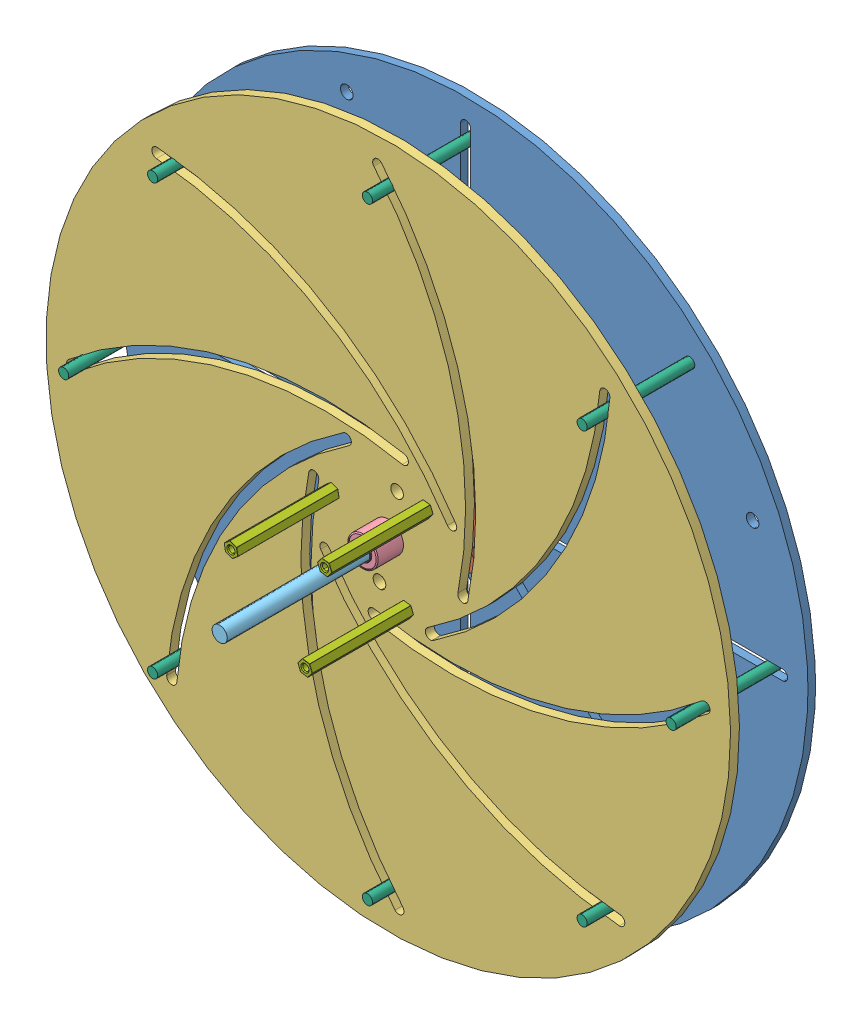
SolidWorks assembly face-clutch-sub, configuration Default. Lengths in mm.
Overall size (318.26 318.26 108.25).
16 component instances, 7 part files, 43 mates.
Components (placement in the parent):
- facePlate-2.0-1: facePlate-2.0 [Default] at origin size (270 270 3)
- flange-coupling-1: flange-coupling [Default] at (0 0 7) x (-1 0 0) z (0 0 -1) size (47 47 20)
- clutchPlate-2.0-1: clutchPlate-2.0 [Default] at (0 0 31.75) x (-0.19867 -0.980066 0) z (0 0 1) size (270 270 3.5)
- LMF6-1: LMF6 [Default] at (0 0 30) x (0.19867 0.980066 0) z (0 0 -1) size (45 45 19)
- shaft-1: shaft [Default] at (0 0 50) x (0.678945 0.734189 0) z (0 0 1) size (6 6 100)
- spoke-1: spoke [Default] at (-84.7044 -84.7044 16.75) x (0.340685 0.940177 0) z (0 0 1) size (4 4 50)
- spoke-2: spoke [Default] at (-119.7901 0 16.75) x (0.626518 0.779407 0) z (0 0 1) size (4 4 50)
- spoke-3: spoke [Default] at (-84.7044 84.7044 16.75) x (-0.525078 0.851054 0) z (0 0 1) size (4 4 50)
- spoke-4: spoke [Default] at (0 119.7901 16.75) x (0.971172 -0.238381 0) z (0 0 1) size (4 4 50)
- spoke-5: spoke [Default] at (84.7044 84.7044 16.75) x (-0.23415 0.9722 0) z (0 0 1) size (4 4 50)
- spoke-6: spoke [Default] at (119.7901 0 16.75) x (-0.955181 0.296022 0) z (0 0 1) size (4 4 50)
- spoke-7: spoke [Default] at (84.7044 -84.7044 16.75) size (4 4 50)
- spoke-8: spoke [Default] at (0 -119.7901 16.75) size (4 4 50)
- TFF-M3x40_DR113.step-1: TFF-M3x40_DR113.step [Default] at (-22.0515 4.4701 73.5) x (0 0 -1) z (-0.344816 -0.93867 0) size (40 5.74 5)
- TFF-M3x40_DR113.step-2: TFF-M3x40_DR113.step [Default] at (14.8969 16.8621 73.5) x (0 0 -1) z (0.79908 -0.601224 0) size (40 5.74 5)
- TFF-M3x40_DR113.step-3: TFF-M3x40_DR113.step [Default] at (7.1546 -21.3322 73.5) x (0 0 -1) z (-0.929232 -0.369496 0) size (40 5.74 5)
Mates (geometry in assembly coordinates):
- Coincident1: coordinate: point of facePlate-2.0-1
- Parallel1: parallel aligned: plane of facePlate-2.0-1 through (0 0 0) normal (0 1 0)
- Concentric1: concentric anti-aligned: cylinder of flange-coupling-1 through (0 0 3) axis (0 0 1) radius 3; cylinder of facePlate-2.0-1 through (0 0 3) axis (0 0 -1) radius 135
- Concentric2: concentric aligned: cylinder of flange-coupling-1 through (8.75 15.1554 23) axis (0 0 -1) radius 2.5; cylinder of facePlate-2.0-1 through (8.75 15.1554 3) axis (0 0 -1) radius 2.5
- Concentric4: concentric aligned: circle of facePlate-2.0-1; circle of clutchPlate-2.0-1
- Distance1: distance = 27 mm anti-aligned: plane of facePlate-2.0-1 through (0 0 3) normal (0 0 1); plane of clutchPlate-2.0-1 through (0 0 30) normal (0 0 -1)
- Coincident4: coincident anti-aligned: plane of facePlate-2.0-1 through (0 0 3) normal (0 0 1); plane of flange-coupling-1 through (0 0 3) normal (0 0 -1)
- Coincident5: coincident anti-aligned: plane of clutchPlate-2.0-1 through (0 0 30) normal (0 0 -1); plane of LMF6-1 through (0 0 30) normal (0 0 1)
- Concentric5: concentric aligned: cylinder of clutchPlate-2.0-1 through (0 0 30) axis (0 0 1) radius 5; cylinder of LMF6-1 through (0 0 25) axis (0 0 1) radius 22.5
- Concentric6: concentric anti-aligned: cylinder of LMF6-1 through (3.4767 17.1512 44) axis (0 0 -1) radius 1.75; cylinder of clutchPlate-2.0-1 through (3.4767 17.1512 30) axis (0 0 1) radius 2.5
- Concentric7: concentric aligned: cylinder of flange-coupling-1 through (0 0 3) axis (0 0 1) radius 3; cylinder of shaft-1 through (0 0 0) axis (0 0 1) radius 3
- Coincident6: coincident aligned: plane of facePlate-2.0-1 through (0 0 0) normal (0 0 -1); plane of shaft-1 through (0 0 0) normal (0 0 -1)
- Slot1: slot aligned: cylinder of spoke-1 through (-84.7044 -84.7044 -8.25) axis (0 0 1) radius 2; cylinder of clutchPlate-2.0-1 through (69.0664 -104.1866 30) axis (0 0 1) radius 153; cylinder of clutchPlate-2.0-1 through (-85.3956 -91.283 30) axis (0 0 1) radius 2
- Slot2: slot anti-aligned: plane of facePlate-2.0-1 through (-22.6274 19.799 3) normal (0.707107 0.707107 0); cylinder of spoke-3 through (-84.7044 84.7044 -8.25) axis (0 0 1) radius 2; cylinder of facePlate-2.0-1 through (-88.3883 88.3883 3) axis (0 0 -1) radius 2
- Width1: width anti-aligned: plane of spoke-1 through (-84.7044 -84.7044 -8.25) normal (0 0 -1); plane of spoke-1 through (-84.7044 -84.7044 41.75) normal (0 0 1); plane of clutchPlate-2.0-1 through (0 0 33.5) normal (0 0 1); plane of facePlate-2.0-1 through (0 0 0) normal (0 0 -1)
- Slot3: slot anti-aligned: cylinder of spoke-1 through (-84.7044 -84.7044 -8.25) axis (0 0 1) radius 2; plane of facePlate-2.0-1 through (-19.799 -22.6274 3) normal (-0.707107 0.707107 0); cylinder of facePlate-2.0-1 through (-88.3883 -88.3883 3) axis (0 0 -1) radius 2
- Slot4: slot anti-aligned: cylinder of spoke-2 through (-119.7901 0 -8.25) axis (0 0 1) radius 2; plane of facePlate-2.0-1 through (-30 -2 3) normal (0 1 0); cylinder of facePlate-2.0-1 through (-125 0 3) axis (0 0 -1) radius 2
- Slot5: slot aligned: cylinder of spoke-2 through (-119.7901 0 -8.25) axis (0 0 1) radius 2; cylinder of clutchPlate-2.0-1 through (-24.8337 -122.5083 30) axis (0 0 1) radius 153; cylinder of clutchPlate-2.0-1 through (-124.9307 -4.163 30) axis (0 0 1) radius 2
- Width2: width anti-aligned: plane of spoke-2 through (-119.7901 0 41.75) normal (0 0 1); plane of spoke-2 through (-119.7901 0 -8.25) normal (0 0 -1); plane of facePlate-2.0-1 through (0 0 0) normal (0 0 -1); plane of clutchPlate-2.0-1 through (0 0 33.5) normal (0 0 1)
- Slot7: slot aligned: cylinder of spoke-3 through (-84.7044 84.7044 -8.25) axis (0 0 1) radius 2; cylinder of clutchPlate-2.0-1 through (-104.1866 -69.0664 30) axis (0 0 1) radius 153; cylinder of clutchPlate-2.0-1 through (-91.283 85.3956 30) axis (0 0 1) radius 2
- Slot8: slot anti-aligned: cylinder of spoke-3 through (-84.7044 84.7044 -8.25) axis (0 0 1) radius 2; cylinder of facePlate-2.0-1 through (-21.2132 21.2132 3) axis (0 0 -1) radius 2; cylinder of facePlate-2.0-1 through (-88.3883 88.3883 3) axis (0 0 -1) radius 2
- Slot9: slot aligned: cylinder of spoke-4 through (0 119.7901 -8.25) axis (0 0 1) radius 2; cylinder of clutchPlate-2.0-1 through (-122.5083 24.8337 30) axis (0 0 1) radius 157; cylinder of clutchPlate-2.0-1 through (-4.163 124.9307 30) axis (0 0 1) radius 2
- Slot10: slot anti-aligned: cylinder of spoke-4 through (0 119.7901 -8.25) axis (0 0 1) radius 2; plane of facePlate-2.0-1 through (2 30 3) normal (-1 0 0); cylinder of facePlate-2.0-1 through (0 30 3) axis (0 0 -1) radius 2
- Width3: width anti-aligned: plane of spoke-4 through (0 119.7901 41.75) normal (0 0 1); plane of spoke-4 through (0 119.7901 -8.25) normal (0 0 -1); plane of facePlate-2.0-1 through (0 0 0) normal (0 0 -1); plane of clutchPlate-2.0-1 through (0 0 33.5) normal (0 0 1)
- Slot11: slot aligned: cylinder of spoke-5 through (84.7044 84.7044 -8.25) axis (0 0 1) radius 2; cylinder of clutchPlate-2.0-1 through (-69.0664 104.1866 30) axis (0 0 1) radius 153; cylinder of clutchPlate-2.0-1 through (85.3956 91.283 30) axis (0 0 1) radius 2
- Slot12: slot anti-aligned: cylinder of spoke-5 through (84.7044 84.7044 -8.25) axis (0 0 1) radius 2; plane of facePlate-2.0-1 through (19.799 22.6274 3) normal (0.707107 -0.707107 0); cylinder of facePlate-2.0-1 through (88.3883 88.3883 3) axis (0 0 -1) radius 2
- Width4: width anti-aligned: plane of spoke-5 through (84.7044 84.7044 -8.25) normal (0 0 -1); plane of spoke-5 through (84.7044 84.7044 41.75) normal (0 0 1); plane of clutchPlate-2.0-1 through (0 0 33.5) normal (0 0 1); plane of facePlate-2.0-1 through (0 0 0) normal (0 0 -1)
- Slot13: slot anti-aligned: cylinder of spoke-6 through (119.7901 0 -8.25) axis (0 0 1) radius 2; plane of facePlate-2.0-1 through (30 -2 3) normal (0 1 0); cylinder of facePlate-2.0-1 through (30 0 3) axis (0 0 -1) radius 2
- Slot14: slot aligned: cylinder of spoke-6 through (119.7901 0 -8.25) axis (0 0 1) radius 2; cylinder of clutchPlate-2.0-1 through (24.8337 122.5083 30) axis (0 0 1) radius 153; cylinder of clutchPlate-2.0-1 through (124.9307 4.163 30) axis (0 0 1) radius 2
- Width5: width anti-aligned: plane of spoke-6 through (119.7901 0 -8.25) normal (0 0 -1); plane of spoke-6 through (119.7901 0 41.75) normal (0 0 1); plane of clutchPlate-2.0-1 through (0 0 33.5) normal (0 0 1); plane of facePlate-2.0-1 through (0 0 0) normal (0 0 -1)
- Slot15: slot aligned: cylinder of spoke-7 through (84.7044 -84.7044 -8.25) axis (0 0 1) radius 2; cylinder of clutchPlate-2.0-1 through (104.1866 69.0664 30) axis (0 0 1) radius 157; cylinder of clutchPlate-2.0-1 through (91.283 -85.3956 30) axis (0 0 1) radius 2
- Slot16: slot anti-aligned: cylinder of spoke-7 through (84.7044 -84.7044 -8.25) axis (0 0 1) radius 2; plane of facePlate-2.0-1 through (19.799 -22.6274 3) normal (0.707107 0.707107 0); cylinder of facePlate-2.0-1 through (21.2132 -21.2132 3) axis (0 0 -1) radius 2
- Width6: width anti-aligned: plane of spoke-7 through (84.7044 -84.7044 -8.25) normal (0 0 -1); plane of spoke-7 through (84.7044 -84.7044 41.75) normal (0 0 1); plane of clutchPlate-2.0-1 through (0 0 33.5) normal (0 0 1); plane of facePlate-2.0-1 through (0 0 0) normal (0 0 -1)
- Slot17: slot aligned: cylinder of spoke-8 through (0 -119.7901 -8.25) axis (0 0 1) radius 2; cylinder of clutchPlate-2.0-1 through (122.5083 -24.8337 30) axis (0 0 1) radius 153; cylinder of clutchPlate-2.0-1 through (4.163 -124.9307 30) axis (0 0 1) radius 2
- Slot18: slot anti-aligned: cylinder of spoke-8 through (0 -119.7901 -8.25) axis (0 0 1) radius 2; plane of facePlate-2.0-1 through (2 -30 3) normal (-1 0 0); cylinder of facePlate-2.0-1 through (0 -125 3) axis (0 0 -1) radius 2
- Width7: width anti-aligned: plane of spoke-8 through (0 -119.7901 -8.25) normal (0 0 -1); plane of spoke-8 through (0 -119.7901 41.75) normal (0 0 1); plane of clutchPlate-2.0-1 through (0 0 33.5) normal (0 0 1); plane of facePlate-2.0-1 through (0 0 0) normal (0 0 -1)
- Width8: width anti-aligned: plane of spoke-3 through (-84.7044 84.7044 41.75) normal (0 0 1); plane of facePlate-2.0-1 through (-84.7044 84.7044 -8.25) normal (0 0 -1); plane of spoke-3 through (0 0 0) normal (0 0 -1); plane of clutchPlate-2.0-1 through (0 0 33.5) normal (0 0 1)
- Concentric9: concentric anti-aligned: circle of TFF-M3x40_DR113.step-1; circle of clutchPlate-2.0-1
- Coincident7: coincident anti-aligned: plane of clutchPlate-2.0-1 through (0 0 33.5) normal (0 0 1); plane of TFF-M3x40_DR113.step-1 through (-22.0515 4.4701 33.5) normal (0 0 -1)
- Concentric10: concentric anti-aligned: circle of TFF-M3x40_DR113.step-2; circle of clutchPlate-2.0-1
- Coincident8: coincident anti-aligned: plane of clutchPlate-2.0-1 through (0 0 33.5) normal (0 0 1); plane of TFF-M3x40_DR113.step-2 through (14.8969 16.8621 33.5) normal (0 0 -1)
- Concentric11: concentric anti-aligned: circle of TFF-M3x40_DR113.step-3; circle of clutchPlate-2.0-1
- Coincident9: coincident anti-aligned: plane of clutchPlate-2.0-1 through (0 0 33.5) normal (0 0 1); plane of TFF-M3x40_DR113.step-3 through (7.1546 -21.3322 33.5) normal (0 0 -1)
